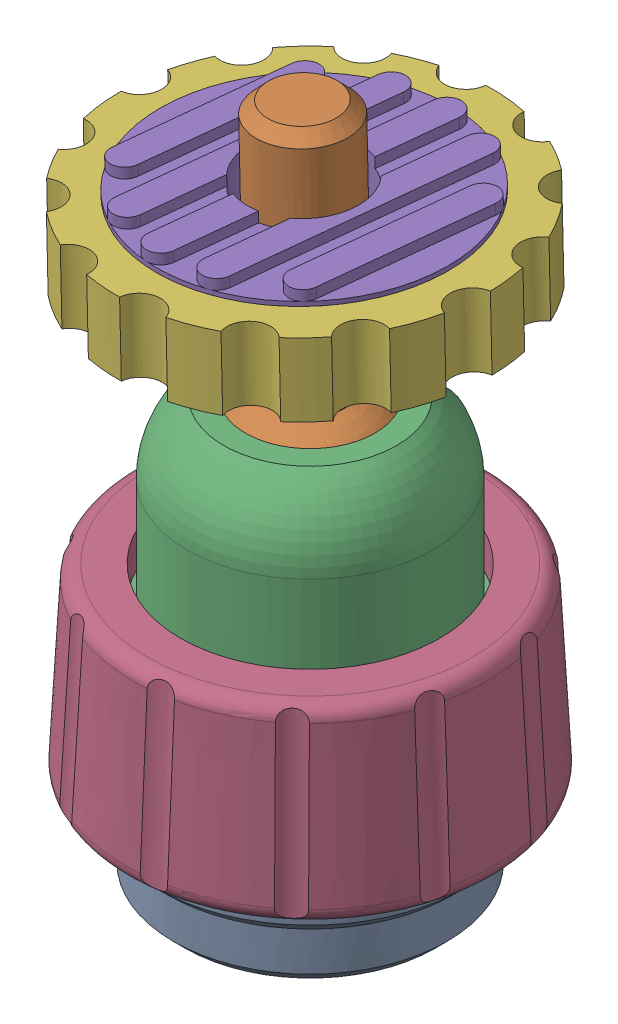
SolidWorks assembly ball joint tripod adapter, configuration Default. Lengths in mm.
Overall size (28.07 46.61 28.09).
6 component instances, 6 part files, 0 mates.
Components (placement in the parent):
- main base-1: main base [Default] at origin size (21.4 19.7 21.4)
- ball joint bolt-1: ball joint bolt [Default] at (0 23.35 0) x (0.99388 0.024332 0.107748) z (-0.107738 -0.001697 0.994178) size (12.8 29.5 12.8)
- bolt house-1: bolt house [Default] at (0 14.1 0) size (19.5 14.8 19.5)
- fastner-1: fastner [Default] at (0 6 0) size (25.73 12.8 25.74)
- friction rubber-1: friction rubber [Default] at (-0.3802 38.9454 -0.0146) x (0.99388 0.024332 0.107748) z (-0.107738 -0.001697 0.994178) size (20 3 20)
- camera base nut-1: camera base nut [Default] at (-0.368 38.4455 -0.0141) x (0.99388 0.024332 0.107748) z (-0.107738 -0.001697 0.994178) size (25.36 5 25.5)
